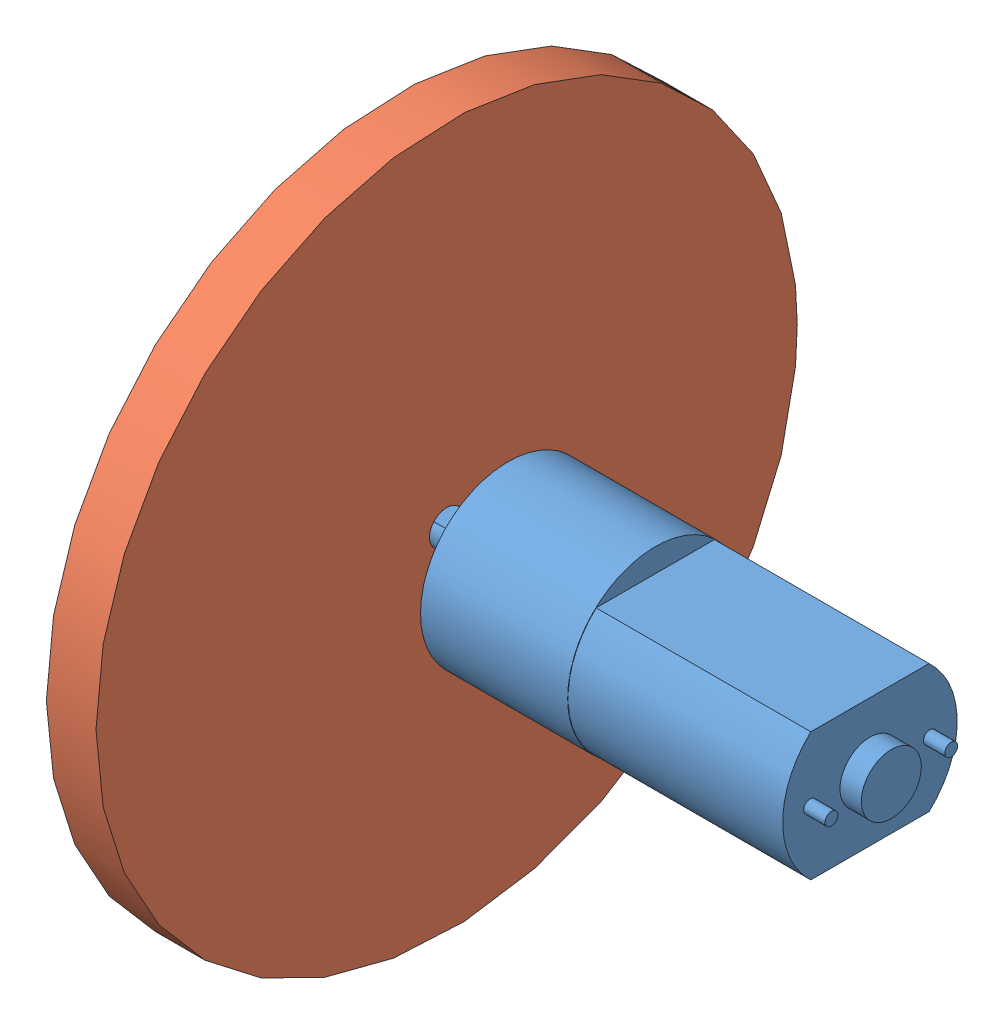
SolidWorks assembly Assem1, configuration Default. Lengths in mm.
Overall size (57.8 82 82).
2 component instances, 2 part files, 2 mates.
Components (placement in the parent):
- PololuMotor_73to1-1: PololuMotor_73to1 [Default] at (-36.3458 6.8547 6.132) size (57.8 20.5 20.5)
- Wheel-1: Wheel [Default] at (-49.3458 6.8547 6.132) x (0 0 -1) z (1 0 0) size (82 82 5.8)
Mates (geometry in assembly coordinates):
- Concentric1: concentric: cylinder of PololuMotor_73to1-1 through (-49.3458 6.8547 6.132) axis (1 0 0) radius 2; cylinder of Wheel-1 through (-43.5458 6.8547 6.132) axis (-1 0 0) radius 2
- Coincident1: coincident aligned: plane of PololuMotor_73to1-1 through (-49.3458 6.8547 6.132) normal (-1 0 0); plane of Wheel-1 through (-49.3458 6.8547 6.132) normal (-1 0 0)
